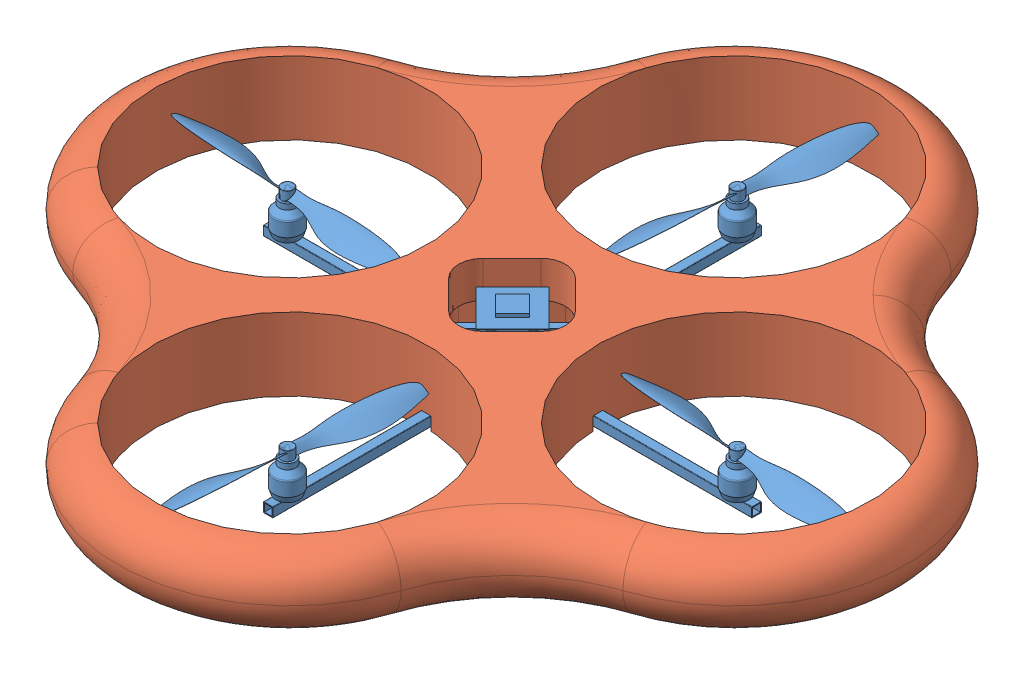
SolidWorks assembly QUADROTOR, MICROKOPTER, TOP ASSY, configuration Default. Lengths in mm.
Overall size (1190.58 91.29 1190.58).
2 component instances, 2 part files, 3 mates.
Components (placement in the parent):
- QUADROTOR, MICROKOPTER, ROUGH-1: QUADROTOR, MICROKOPTER, ROUGH [Default] at (-151.7562 50.16 46.0017) size (733.36 83.04 733.36)
- sexy prop guard top-1: sexy prop guard top [Default] at (-151.6798 15.791 46.5157) x (0.707107 0 0.707107) z (-0.707107 0 0.707107) size (841.87 76.21 841.87)
Mates (geometry in assembly coordinates):
- Angle1: planar angle = 0.785398 rad aligned: plane of sexy prop guard top-1 through (-151.6798 15.791 46.5157) normal (-0.707107 0 0.707107); plane of QUADROTOR, MICROKOPTER, ROUGH-1 through (-151.7562 50.16 46.0017) normal (0 0 1)
- Parallel1: parallel aligned: plane of QUADROTOR, MICROKOPTER, ROUGH-1 through (-151.7562 50.16 46.0017) normal (0 1 0); plane of sexy prop guard top-1
- Coincident2: coincident anti-aligned: plane of QUADROTOR, MICROKOPTER, ROUGH-1 through (103.2438 55.161 50.5027) normal (0 1 0); plane of sexy prop guard top-1 through (-76.4657 55.161 46.5157) normal (0 -1 0)
